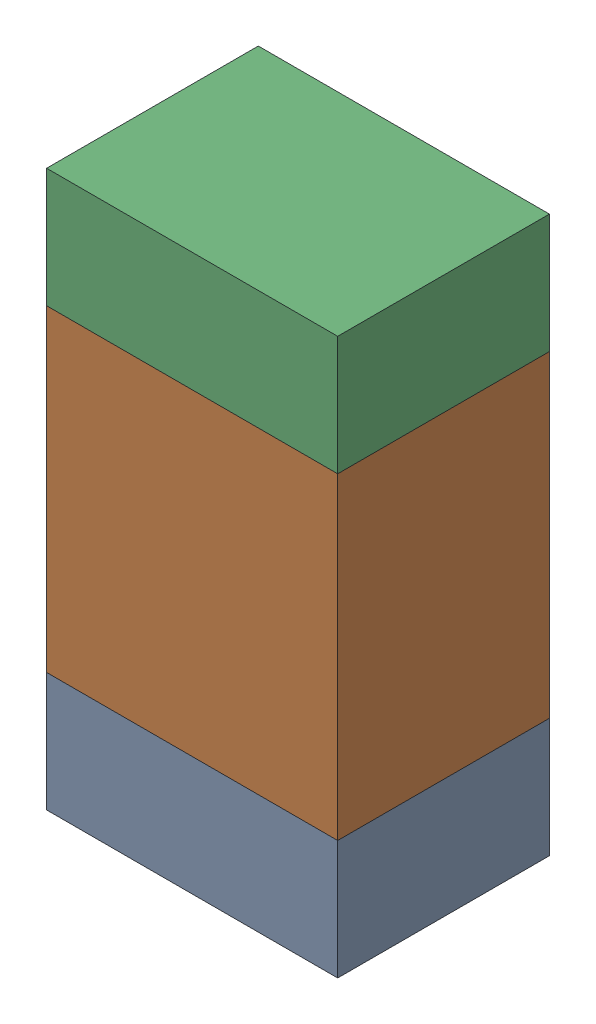
SolidWorks assembly R112_2PCB, configuration Default. Lengths in mm.
Overall size (0.55 1.05 0.4).
6 component instances, 2 part files, 0 mates.
Components (placement in the parent):
- 846483288-1: 846483288 [Default] at (115.6999 89.3876 0) size (0.55 0.22 0.4)
  - Extruded_12-1: Extruded_12 [Default] at origin size (0.55 0.22 0.4)
- 846483424-1: 846483424 [Default] at (115.6999 89.8001 0) size (0.55 0.6 0.4)
  - Extruded_13-1: Extruded_13 [Default] at origin size (0.55 0.6 0.4)
- 846483288-2: 846483288 [Default] at (115.6999 90.2126 0) size (0.55 0.22 0.4)
  - Extruded_12-1: Extruded_12 [Default] at origin size (0.55 0.22 0.4)
